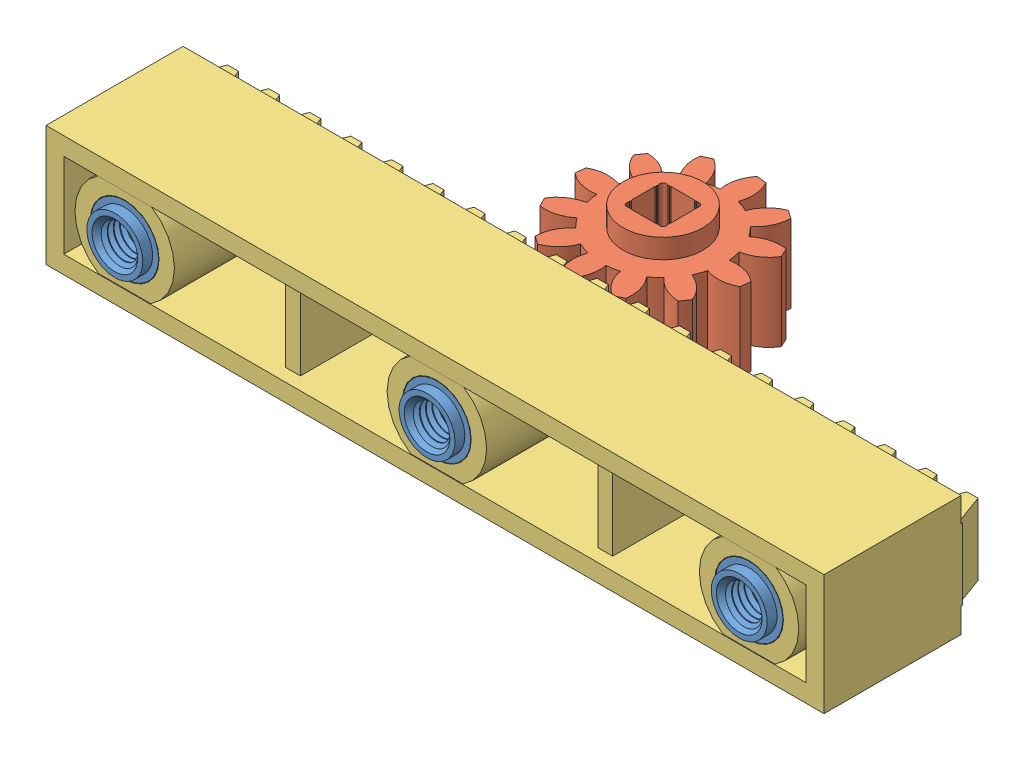
SolidWorks assembly RACK-ASSY, configuration Default. Lengths in mm.
Overall size (63.3 9.8 27.93).
5 component instances, 3 part files, 0 mates.
Components (placement in the parent):
- INSERT-NUT-1: INSERT-NUT [Default] at (-25.2 0 1.7) x (-1 0 0) z (0 1 0) size (5.68 9.43 5.68)
- INSERT-NUT-2: INSERT-NUT [Default] at (25.6 0 1.7) x (-1 0 0) z (0 1 0) size (5.68 9.43 5.68)
- 12-TOOTH-GEAR-1: 12-TOOTH-GEAR [Default] at (-1 0 -9.4) x (1 0 0) z (0 1 0) size (14.8 14.8 9.53)
- RACK-1: RACK [Default] at origin size (63.3 9.8 13.65)
- INSERT-NUT-3: INSERT-NUT [Default] at (0.2 0 1.7) x (-1 0 0) z (0 1 0) size (5.68 9.43 5.68)
